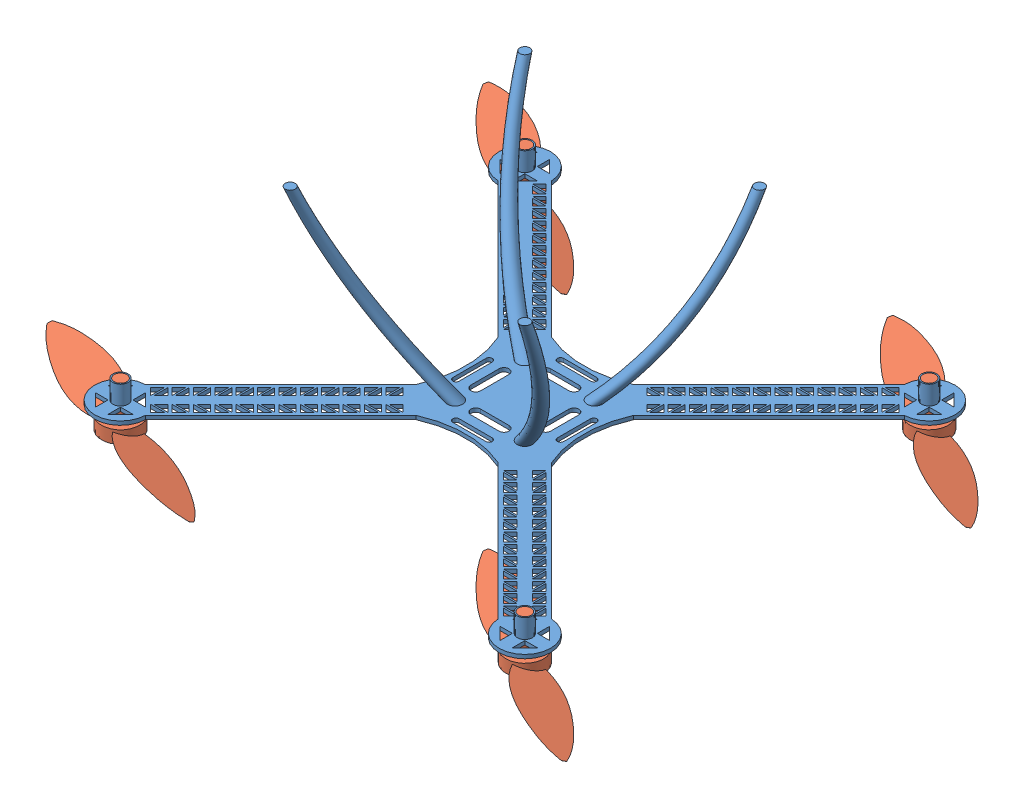
SolidWorks assembly quadcopter430assemblyrecreation, configuration Default. Lengths in mm.
Overall size (523.15 167.91 467.19).
5 component instances, 2 part files, 8 mates.
Components (placement in the parent):
- quadcopterf430-1: quadcopterf430 [Default] at (126.6733 162.4042 284.5343) size (362.05 150.01 362.05)
- 430propeller-1: 430propeller [Default] at (-33.8514 155.4042 445.059) x (-0.920868 0 -0.389875) z (-0.389875 0 0.920868) size (210 35.9 37.37)
- 430propeller-4: 430propeller [Default] at (287.1981 155.4042 445.059) x (-0.837169 0 -0.546944) z (-0.546944 0 0.837169) size (210 35.9 37.37)
- 430propeller-5: 430propeller [Default] at (287.1981 155.4042 124.0096) x (-0.837169 0 -0.546944) z (-0.546944 0 0.837169) size (210 35.9 37.37)
- 430propeller-6: 430propeller [Default] at (-33.8514 155.4042 124.0096) x (-0.837169 0 -0.546944) z (-0.546944 0 0.837169) size (210 35.9 37.37)
Mates (geometry in assembly coordinates):
- Concentric1: concentric anti-aligned: cylinder of quadcopterf430-1 through (-33.8514 162.4042 445.059) axis (0 1 0) radius 5; cylinder of 430propeller-1 through (-33.8514 180.4042 445.059) axis (0 -1 0) radius 5
- Coincident4: coincident aligned: plane of quadcopterf430-1 through (-33.8514 180.4042 445.059) normal (0 1 0); plane of 430propeller-1 through (-33.8514 180.4042 445.059) normal (0 1 0)
- Concentric4: concentric anti-aligned: cylinder of quadcopterf430-1 through (287.1981 162.4042 445.059) axis (0 1 0) radius 5; cylinder of 430propeller-4 through (287.1981 180.4042 445.059) axis (0 -1 0) radius 5
- Coincident5: coincident aligned: plane of quadcopterf430-1 through (287.1981 180.4042 445.059) normal (0 1 0); plane of 430propeller-4 through (287.1981 180.4042 445.059) normal (0 1 0)
- Concentric5: concentric anti-aligned: cylinder of quadcopterf430-1 through (-33.8514 162.4042 124.0096) axis (0 1 0) radius 5; cylinder of 430propeller-6 through (-33.8514 180.4042 124.0096) axis (0 -1 0) radius 5
- Coincident6: coincident aligned: plane of quadcopterf430-1 through (-33.8514 180.4042 124.0096) normal (0 1 0); plane of 430propeller-6 through (-33.8514 180.4042 124.0096) normal (0 1 0)
- Concentric6: concentric anti-aligned: cylinder of quadcopterf430-1 through (287.1981 162.4042 124.0096) axis (0 1 0) radius 5; cylinder of 430propeller-5 through (287.1981 180.4042 124.0096) axis (0 -1 0) radius 5
- Coincident7: coincident aligned: plane of quadcopterf430-1 through (287.1981 180.4042 124.0096) normal (0 1 0); plane of 430propeller-5 through (287.1981 180.4042 124.0096) normal (0 1 0)
